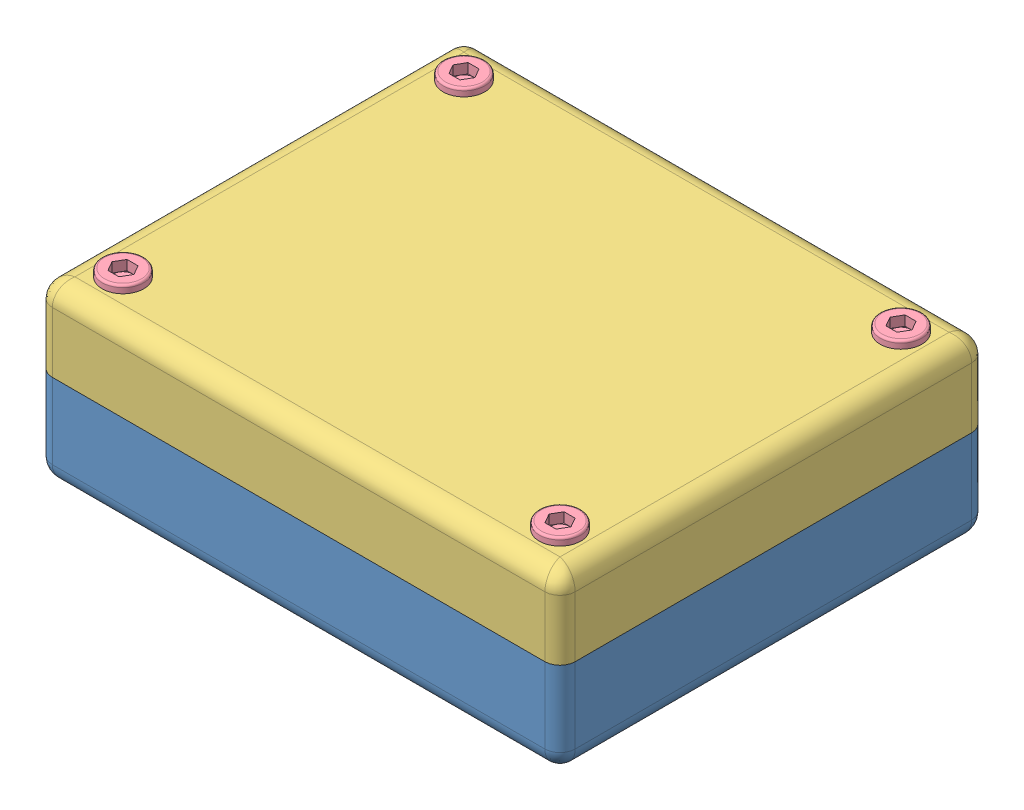
SolidWorks assembly Housing, configuration Standard. Lengths in mm.
Overall size (69.14 24 56.44).
11 component instances, 5 part files, 26 mates.
Components (placement in the parent):
- Housing-Bottom-1: Housing-Bottom [Standard] at (-45.7424 0.8274 115) size (69.14 12.5 56.44)
- Audio-Switch-1: Audio-Switch [Standard] at (-43.2424 7.1274 112.5) x (1 0 0) z (0 1 0) size (64.14 51.44 1.6)
- Housing-Top-1: Housing-Top [Standard] at (-45.7424 21.3274 115) size (69.14 15.9 56.44)
- socket head cap screw_din-1: socket head cap screw_din [DIN 912 M3 x 20 --- 20S] at (17.7176 24.8274 109.325) x (0 -1 0) z (0 0 1) size (23 5.5 5.5)
- socket head cap screw_din-2: socket head cap screw_din [DIN 912 M3 x 20 --- 20S] at (-40.0674 24.8274 64.24) x (0 -1 0) z (0 0 1) size (23 5.5 5.5)
- socket head cap screw_din-3: socket head cap screw_din [DIN 912 M3 x 20 --- 20S] at (-40.0674 24.8274 109.325) x (0 -1 0) z (0 0 1) size (23 5.5 5.5)
- socket head cap screw_din-4: socket head cap screw_din [DIN 912 M3 x 20 --- 20S] at (17.7176 24.8274 64.24) x (0 -1 0) z (0 0 1) size (23 5.5 5.5)
- hex thin nut chamfered gradeab_din-1: hex thin nut chamfered gradeab_din [Hexagon Thin Nut ISO 4035 - M3 - S] at (-40.0674 2.8274 109.325) x (1 0 0) z (0 1 0) size (5.5 6.35 1.8)
- hex thin nut chamfered gradeab_din-2: hex thin nut chamfered gradeab_din [Hexagon Thin Nut ISO 4035 - M3 - S] at (-40.0674 2.8274 64.24) x (1 0 0) z (0 1 0) size (5.5 6.35 1.8)
- hex thin nut chamfered gradeab_din-3: hex thin nut chamfered gradeab_din [Hexagon Thin Nut ISO 4035 - M3 - S] at (17.7176 2.8274 64.24) x (1 0 0) z (0 1 0) size (5.5 6.35 1.8)
- hex thin nut chamfered gradeab_din-4: hex thin nut chamfered gradeab_din [Hexagon Thin Nut ISO 4035 - M3 - S] at (17.7176 2.8274 109.325) x (1 0 0) z (0 1 0) size (5.5 6.35 1.8)
Mates (geometry in assembly coordinates):
- Deckungsgleich2: coincident anti-aligned: plane of Housing-Bottom-1 through (-43.2424 13.3274 112.5) normal (0 0 -1); plane of Audio-Switch-1 through (-43.2424 7.1274 112.5) normal (0 0 1)
- Deckungsgleich3: coincident anti-aligned: plane of Housing-Bottom-1 through (-43.2424 13.3274 112.5) normal (1 0 0); plane of Audio-Switch-1 through (-43.2424 7.1274 112.5) normal (-1 0 0)
- Deckungsgleich4: coincident anti-aligned: plane of Housing-Bottom-1 through (-40.0674 6.3274 109.325) normal (0 1 0); plane of Audio-Switch-1 through (-43.2424 6.3274 112.5) normal (0 -1 0)
- Deckungsgleich5: coincident anti-aligned: plane of Housing-Bottom-1 through (-43.7424 13.3274 60.565) normal (0 1 0); plane of Housing-Top-1 through (-45.7424 13.3274 115) normal (0 -1 0)
- Deckungsgleich6: coincident aligned: plane of Housing-Bottom-1 through (-45.7424 3.3274 113) normal (-1 0 0); plane of Housing-Top-1 through (-45.7424 23.8274 113) normal (-1 0 0)
- Deckungsgleich7: coincident aligned: plane of Housing-Bottom-1 through (-43.7424 3.3274 115) normal (0 0 1); plane of Housing-Top-1 through (-43.7424 23.8274 115) normal (0 0 1)
- Deckungsgleich8: coincident anti-aligned: plane of Housing-Top-1 through (-40.0674 21.8274 64.24) normal (0 1 0); plane of socket head cap screw_din-2 through (-37.3174 21.8274 64.24) normal (0 -1 0)
- Deckungsgleich9: coincident anti-aligned: plane of Housing-Top-1 through (-40.0674 21.8274 109.325) normal (0 1 0); plane of socket head cap screw_din-3 through (-37.3174 21.8274 109.325) normal (0 -1 0)
- Deckungsgleich10: coincident anti-aligned: plane of Housing-Top-1 through (17.7176 21.8274 64.24) normal (0 1 0); plane of socket head cap screw_din-4 through (20.4676 21.8274 64.24) normal (0 -1 0)
- Deckungsgleich11: coincident anti-aligned: plane of Housing-Top-1 through (17.7176 21.8274 109.325) normal (0 1 0); plane of socket head cap screw_din-1 through (20.4676 21.8274 109.325) normal (0 -1 0)
- Konzentrisch1: concentric anti-aligned: cylinder of Housing-Top-1 through (-40.0674 23.8274 64.24) axis (0 -1 0) radius 1.5; cylinder of socket head cap screw_din-2 through (-40.0674 56.5774 64.24) axis (0 1 0) radius 1.5
- Konzentrisch2: concentric anti-aligned: cylinder of Housing-Top-1 through (-40.0674 23.8274 109.325) axis (0 -1 0) radius 1.5; cylinder of socket head cap screw_din-3 through (-40.0674 56.5774 109.325) axis (0 1 0) radius 1.5
- Konzentrisch3: concentric anti-aligned: cylinder of Housing-Top-1 through (17.7176 23.8274 64.24) axis (0 -1 0) radius 1.5; cylinder of socket head cap screw_din-4 through (17.7176 56.5774 64.24) axis (0 1 0) radius 1.5
- Konzentrisch4: concentric anti-aligned: cylinder of Housing-Top-1 through (17.7176 23.8274 109.325) axis (0 -1 0) radius 1.5; cylinder of socket head cap screw_din-1 through (17.7176 56.5774 109.325) axis (0 1 0) radius 1.5
- Deckungsgleich12: coincident: plane of Housing-Bottom-1 through (-45.7424 2.8274 115) normal (0 -1 0); plane of hex thin nut chamfered gradeab_din-4 through (17.7176 2.8274 104.337) normal (0 1 0)
- Deckungsgleich13: coincident: plane of Housing-Bottom-1 through (-45.7424 2.8274 115) normal (0 -1 0); plane of hex thin nut chamfered gradeab_din-3 through (18.4476 2.8274 61.486) normal (0 1 0)
- Deckungsgleich15: coincident: plane of Housing-Bottom-1 through (-45.7424 2.8274 115) normal (0 -1 0); plane of hex thin nut chamfered gradeab_din-1 through (-40.0674 2.8274 106.1496) normal (0 1 0)
- Deckungsgleich16: coincident: plane of Housing-Bottom-1 through (-45.7424 2.8274 115) normal (0 -1 0); plane of hex thin nut chamfered gradeab_din-2 through (-40.0674 2.8274 61.0646) normal (0 1 0)
- Deckungsgleich17: coincident: plane of Housing-Bottom-1 through (20.4676 2.8274 107.7373) normal (-1 0 0); plane of hex thin nut chamfered gradeab_din-4 through (20.4676 1.0274 107.7373) normal (1 0 0)
- Deckungsgleich18: coincident anti-aligned: plane of Housing-Bottom-1 through (20.4676 2.8274 110.9127) normal (-0.5 0 -0.866025); plane of hex thin nut chamfered gradeab_din-4 through (17.7176 1.0274 112.5004) normal (0.5 0 0.866025)
- Deckungsgleich19: coincident: plane of Housing-Bottom-1 through (17.7176 2.8274 61.0646) normal (-0.5 0 0.866025); plane of hex thin nut chamfered gradeab_din-3 through (20.4676 1.0274 62.6523) normal (0.5 0 -0.866025)
- Deckungsgleich20: coincident anti-aligned: plane of Housing-Bottom-1 through (14.9676 2.8274 62.6523) normal (0.5 0 0.866025); plane of hex thin nut chamfered gradeab_din-3 through (17.7176 1.0274 61.0646) normal (-0.5 0 -0.866025)
- Deckungsgleich21: coincident: plane of Housing-Bottom-1 through (-40.0674 2.8274 106.1496) normal (-0.5 0 0.866025); plane of hex thin nut chamfered gradeab_din-1 through (-37.3174 1.0274 107.7373) normal (0.5 0 -0.866025)
- Deckungsgleich22: coincident anti-aligned: plane of Housing-Bottom-1 through (-37.3174 2.8274 107.7373) normal (-1 0 0); plane of hex thin nut chamfered gradeab_din-1 through (-37.3174 1.0274 107.7373) normal (1 0 0)
- Deckungsgleich23: coincident: plane of Housing-Bottom-1 through (-37.3174 2.8274 65.8277) normal (-0.5 0 -0.866025); plane of hex thin nut chamfered gradeab_din-2 through (-40.0674 1.0274 67.4154) normal (0.5 0 0.866025)
- Deckungsgleich24: coincident anti-aligned: plane of Housing-Bottom-1 through (-37.3174 2.8274 62.6523) normal (-1 0 0); plane of hex thin nut chamfered gradeab_din-2 through (-37.3174 1.0274 62.6523) normal (1 0 0)
